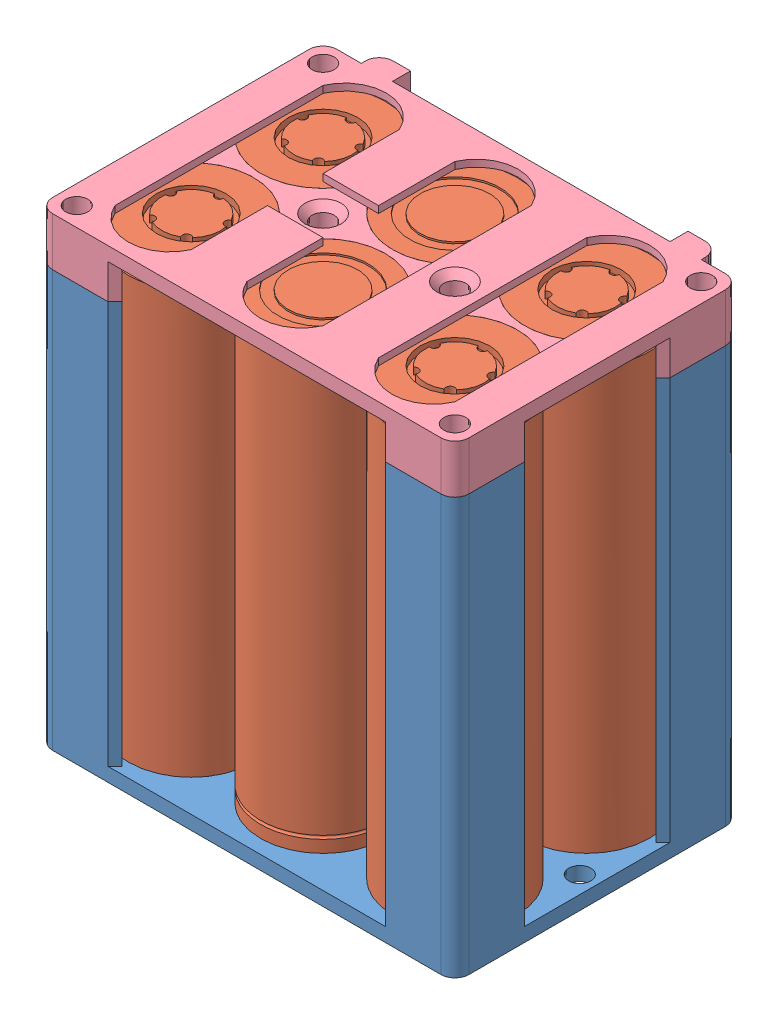
SolidWorks assembly assembly, configuration Domyślna. Lengths in mm.
Overall size (60 67 46.06).
9 component instances, 4 part files, 17 mates.
Components (placement in the parent):
- BatteryBoxPart1-1: BatteryBoxPart1 [Domyślna] at (-16.7581 -36.8359 81.8) size (60 60 43.6)
- LiIonBattery-1: LiIonBattery [Domyślna] at (-27.7581 -35.8359 51.8) size (18 65 18)
- LiIonBattery-2: LiIonBattery [Domyślna] at (-46.7581 29.1641 51.8) x (-0.837169 0 -0.546944) z (-0.546944 0 0.837169) size (18 65 18)
- LiIonBattery-3: LiIonBattery [Domyślna] at (-27.7581 -35.8359 70.8) size (18 65 18)
- LiIonBattery-4: LiIonBattery [Domyślna] at (-65.7581 -35.8359 51.8) size (18 65 18)
- LiIonBattery-5: LiIonBattery [Domyślna] at (-65.7581 -35.8359 70.8) size (18 65 18)
- LiIonBattery-6: LiIonBattery [Domyślna] at (-46.7581 29.1641 70.8) x (-0.837169 0 -0.546944) z (-0.546944 0 0.837169) size (18 65 18)
- 3s 25A BMS with balance-2: 3s 25A BMS with balance [Default] at (-48.0403 -1.9588 40.8) x (0 1 0) z (-1 0 0) size (56 3.6 45)
- BatteryBoxPart2-1: BatteryBoxPart2 [Domyślna] at (-16.7581 30.1641 40.8) x (1 0 0) z (0 -1 0) size (60 43.6 11)
Mates (geometry in assembly coordinates):
- Concentric1: concentric anti-aligned: cylinder of BatteryBoxPart1-1 through (-27.7581 -35.8359 51.8) axis (0 1 0) radius 9; cylinder of LiIonBattery-1 through (-27.7581 29.1641 51.8) axis (0 -1 0) radius 9
- Coincident2: coincident aligned: circle of BatteryBoxPart1-1; circle of LiIonBattery-1
- Concentric3: concentric anti-aligned: cylinder of BatteryBoxPart1-1 through (-27.7581 -35.8359 70.8) axis (0 1 0) radius 9; cylinder of LiIonBattery-3 through (-27.7581 29.1641 70.8) axis (0 -1 0) radius 9
- Coincident4: coincident aligned: circle of BatteryBoxPart1-1; circle of LiIonBattery-3
- Concentric4: concentric aligned: cylinder of BatteryBoxPart1-1 through (-46.7581 -35.8359 51.8) axis (0 1 0) radius 9; cylinder of LiIonBattery-2 through (-46.7581 -35.8359 51.8) axis (0 1 0) radius 9
- Coincident5: coincident anti-aligned: circle of BatteryBoxPart1-1; circle of LiIonBattery-2
- Concentric5: concentric aligned: cylinder of BatteryBoxPart1-1 through (-46.7581 -35.8359 70.8) axis (0 1 0) radius 9; cylinder of LiIonBattery-6 through (-46.7581 -35.8359 70.8) axis (0 1 0) radius 9
- Coincident6: coincident anti-aligned: circle of BatteryBoxPart1-1; circle of LiIonBattery-6
- Concentric6: concentric anti-aligned: cylinder of BatteryBoxPart1-1 through (-65.7581 -35.8359 51.8) axis (0 1 0) radius 9; cylinder of LiIonBattery-4 through (-65.7581 29.1641 51.8) axis (0 -1 0) radius 9
- Coincident7: coincident aligned: circle of BatteryBoxPart1-1; circle of LiIonBattery-4
- Concentric7: concentric anti-aligned: cylinder of BatteryBoxPart1-1 through (-65.7581 -35.8359 70.8) axis (0 1 0) radius 9; cylinder of LiIonBattery-5 through (-65.7581 29.1641 70.8) axis (0 -1 0) radius 9
- Coincident8: coincident aligned: circle of BatteryBoxPart1-1; circle of LiIonBattery-5
- Coincident15: coincident anti-aligned: line of BatteryBoxPart1-1 through (-24.2581 -34.8359 40.8) axis (0 1 0); line of 3s 25A BMS with balance-2 through (-24.2581 21.1641 40.8) axis (0 -1 0)
- Coincident16: coincident anti-aligned: line of BatteryBoxPart1-1 through (-69.2581 19.1641 40.8) axis (0 -1 0); line of 3s 25A BMS with balance-2 through (-69.2581 -34.8359 40.8) axis (0 1 0)
- Coincident17: coincident aligned: line of BatteryBoxPart1-1 through (-69.2581 -34.8359 39.2) axis (0 0 1); line of 3s 25A BMS with balance-2 through (-69.2581 -34.8359 39.6) axis (0 0 1)
- Coincident18: coincident anti-aligned: plane of BatteryBoxPart1-1 through (-27.7581 23.1641 70.8) normal (0 1 0); plane of BatteryBoxPart2-1 through (-27.7581 23.1641 70.8) normal (0 -1 0)
- Coincident19: coincident aligned: line of BatteryBoxPart1-1 through (-16.7581 23.1641 79.8) axis (0 -1 0); line of BatteryBoxPart2-1 through (-16.7581 30.1641 79.8) axis (0 -1 0)
